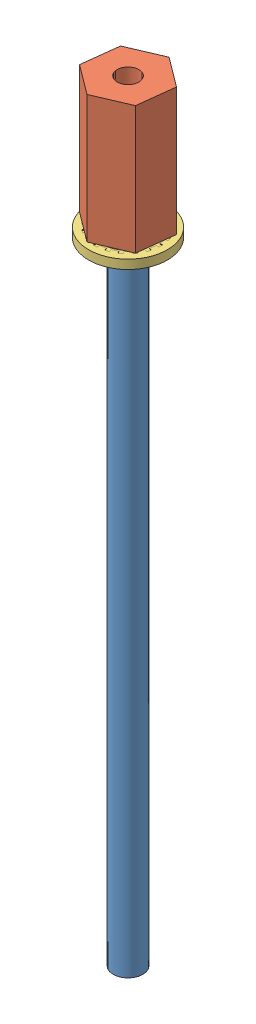
SolidWorks assembly BiasAndInnerCurvatureFeedthrough, configuration Default. Lengths in mm.
Overall size (9.78 95.76 10.04).
3 component instances, 3 part files, 4 mates.
Components (placement in the parent):
- BiasAndInnerCurvatureFeedtrough-1: BiasAndInnerCurvatureFeedtrough [Default] at (-7.706 -33.6022 8.3446) size (3.68 84.96 3.68)
- CurrentConnector-1: CurrentConnector [Default] at (-7.706 46.2808 8.3446) x (0.118539 0 -0.992949) z (0.992949 0 0.118539) size (9.17 15.88 7.94)
- 93783A007_PRESSURE-SEALING WASHER FOR SCREWS AND BOLTS-1: 93783A007_PRESSURE-SEALING WASHER FOR SCREWS AND BOLTS [93783A007] at (-7.706 45.3309 8.3446) size (9.78 1.9 9.78)
Mates (geometry in assembly coordinates):
- Concentric1: concentric: cylinder of BiasAndInnerCurvatureFeedtrough-1 through (-7.706 51.3608 8.3446) axis (0 -1 0) radius 1.8415; cylinder of CurrentConnector-1 through (-7.706 46.2808 8.3446) axis (0 -1 0) radius 1.3526
- Coincident1: coincident: plane of BiasAndInnerCurvatureFeedtrough-1 through (-7.706 51.3608 8.3446) normal (0 1 0); circle of CurrentConnector-1
- Tangent5: tangent: plane of CurrentConnector-1 through (-7.706 46.2808 8.3446) normal (0 -1 0); torus of 93783A007_PRESSURE-SEALING WASHER FOR SCREWS AND BOLTS-1
- Concentric4: concentric: cylinder of BiasAndInnerCurvatureFeedtrough-1 through (-7.706 51.3608 8.3446) axis (0 -1 0) radius 1.8415; cylinder of 93783A007_PRESSURE-SEALING WASHER FOR SCREWS AND BOLTS-1 through (-7.706 45.3309 8.3446) axis (0 -1 0) radius 4.8895
